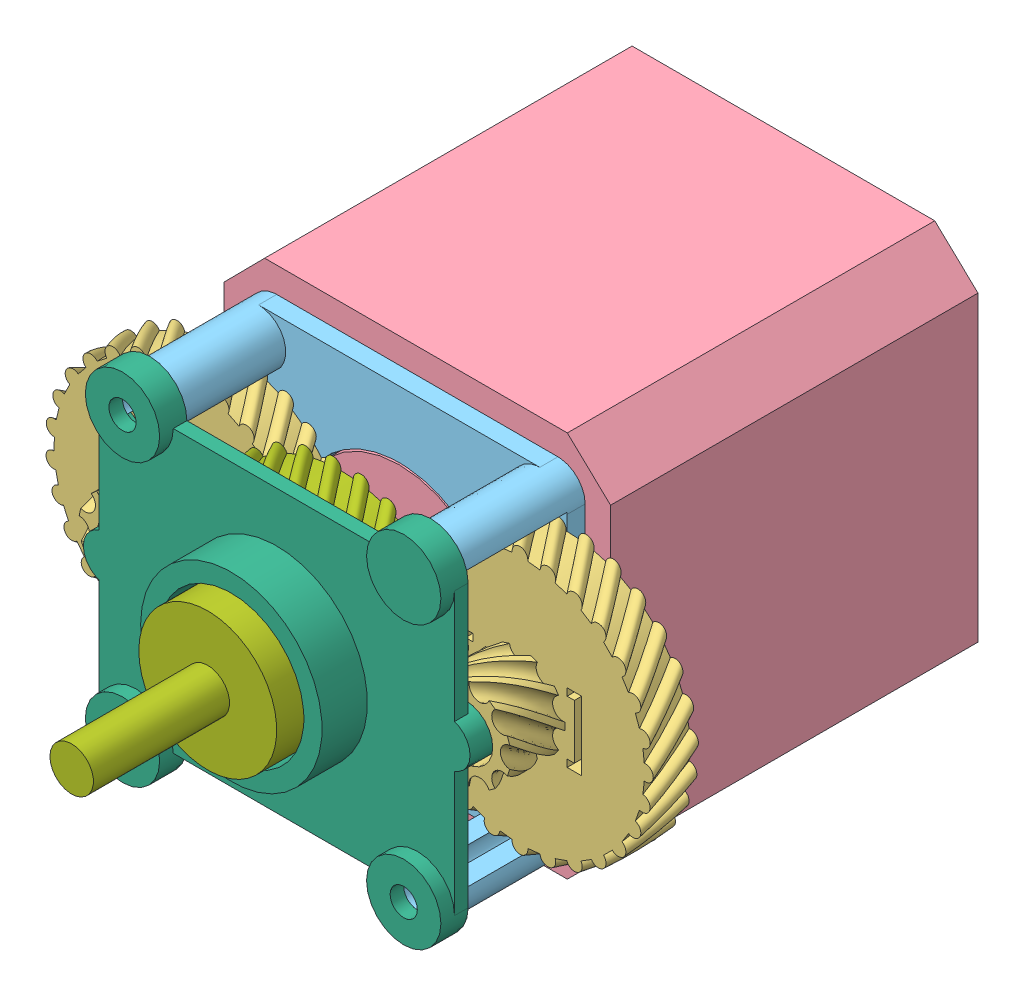
SolidWorks assembly GearStepperMotor, configuration Default. Lengths in mm.
Overall size (68.55 42.6 78.6).
8 component instances, 7 part files, 15 mates.
Components (placement in the parent):
- GearVtulka-1: GearVtulka [Default] at (-0.6199 -0.4892 -3.2366) size (12 12 19.05)
- GearPressSLDPRT-1: GearPressSLDPRT [Default] at (-0.6199 -0.4892 -2.2366) size (11.2 11.2 13.57)
- GearRot1-1: GearRot1 [Default] at (-19.4334 -1.1462 -8.2366) x (0.994717 0.102659 0) z (0 0 1) size (29.49 29.49 11)
- STP_MTR-1: STP_MTR [Default] at (20.6801 3.6108 -10.7366) x (-1 0 0) z (0 0 -1) size (42.6 42.6 60.5)
- BOTTOM-1: BOTTOM [Default] at (-0.6199 -0.4892 -10.7366) x (0 1 0) z (0 0 1) size (37 42.66 15.5)
- GearRot1-2: GearRot1 [Default] at (18.1935 0.1678 -8.2366) size (29.49 29.49 11)
- GEAR_TOP-1: GEAR_TOP [Default] at (-0.6199 -0.4892 3.2634) size (42.63 39.2 15.9)
- GearRot2-1: GearRot2 [Default] at (-0.6199 -0.4892 -2.2366) size (29.49 29.49 29.6)
Mates (geometry in assembly coordinates):
- Concentric1: concentric aligned: cylinder of GearVtulka-1 through (-0.6199 -0.4892 -2.7366) axis (0 0 -1) radius 2.6; cylinder of GearPressSLDPRT-1 through (-0.6199 -0.4892 9.2634) axis (0 0 -1) radius 4.9
- Coincident1: coincident anti-aligned: plane of GearVtulka-1 through (-0.6199 -0.4892 -2.2366) normal (0 0 1); plane of GearPressSLDPRT-1 through (-0.6199 -0.4892 -2.2366) normal (0 0 -1)
- Parallel4: parallel aligned: plane of GearVtulka-1 through (-0.6199 -0.4892 -8.2366) normal (0 0 -1); plane of GearRot1-1 through (-19.4334 -1.1462 -8.2366) normal (0 0 -1)
- Concentric5: concentric aligned: cylinder of STP_MTR-1 through (-0.6199 -0.4892 9.2634) axis (0 0 -1) radius 2.5; cylinder of GearVtulka-1 through (-0.6199 -0.4892 -2.7366) axis (0 0 -1) radius 2.6
- Coincident3: coincident anti-aligned: plane of GearPressSLDPRT-1 through (-0.6199 -0.4892 9.2634) normal (0 0 -1); plane of STP_MTR-1 through (-0.6199 -0.4892 9.2634) normal (0 0 1)
- Concentric7: concentric anti-aligned: cylinder of STP_MTR-1 through (-16.1199 -15.9892 -51.2366) axis (0 0 1) radius 1.5; cylinder of BOTTOM-1 through (-16.1199 -15.9892 -8.7366) axis (0 0 -1) radius 1.5
- Concentric8: concentric anti-aligned: cylinder of STP_MTR-1 through (-16.1199 15.0108 -51.2366) axis (0 0 1) radius 1.5; cylinder of BOTTOM-1 through (-16.1199 15.0108 -8.7366) axis (0 0 -1) radius 1.5
- Coincident5: coincident anti-aligned: plane of STP_MTR-1 through (20.6801 20.8108 -10.7366) normal (0 0 1); plane of BOTTOM-1 through (-16.1199 15.0108 -10.7366) normal (0 0 -1)
- Concentric13: concentric anti-aligned: cylinder of GearRot1-1 through (-19.4334 -1.1462 -8.2387) axis (0 0 1) radius 3; cylinder of BOTTOM-1 through (-19.4334 -1.1462 -8.7366) axis (0 0 -1) radius 2.496
- Coincident6: coincident aligned: plane of GearVtulka-1 through (-0.6199 -0.4892 -8.2366) normal (0 0 -1); plane of GearRot1-2 through (18.1935 0.1678 -8.2366) normal (0 0 -1)
- Concentric14: concentric anti-aligned: cylinder of BOTTOM-1 through (18.1935 0.1678 -8.7366) axis (0 0 -1) radius 2.5302; cylinder of GearRot1-2 through (18.1935 0.1678 -8.2387) axis (0 0 1) radius 3
- Concentric17: concentric aligned: cylinder of BOTTOM-1 through (-16.1199 -15.9892 -8.7366) axis (0 0 -1) radius 3; cylinder of GEAR_TOP-1 through (-16.1199 -15.9892 4.7634) axis (0 0 -1) radius 3.1
- Coincident8: coincident anti-aligned: plane of BOTTOM-1 through (-16.1199 -15.9892 4.7634) normal (0 0 1); plane of GEAR_TOP-1 through (-16.1199 -15.9892 4.7634) normal (0 0 -1)
- Concentric18: concentric aligned: cylinder of GearPressSLDPRT-1 through (-0.6199 -0.4892 9.2634) axis (0 0 -1) radius 4.9; cylinder of GearRot2-1 through (-0.6199 -0.4892 2.7709) axis (0 0 -1) radius 7.6
- Coincident9: coincident anti-aligned: plane of GearVtulka-1 through (-0.6199 -0.4892 -2.2366) normal (0 0 1); plane of GearRot2-1 through (-0.6199 -0.4892 -2.2366) normal (0 0 -1)
